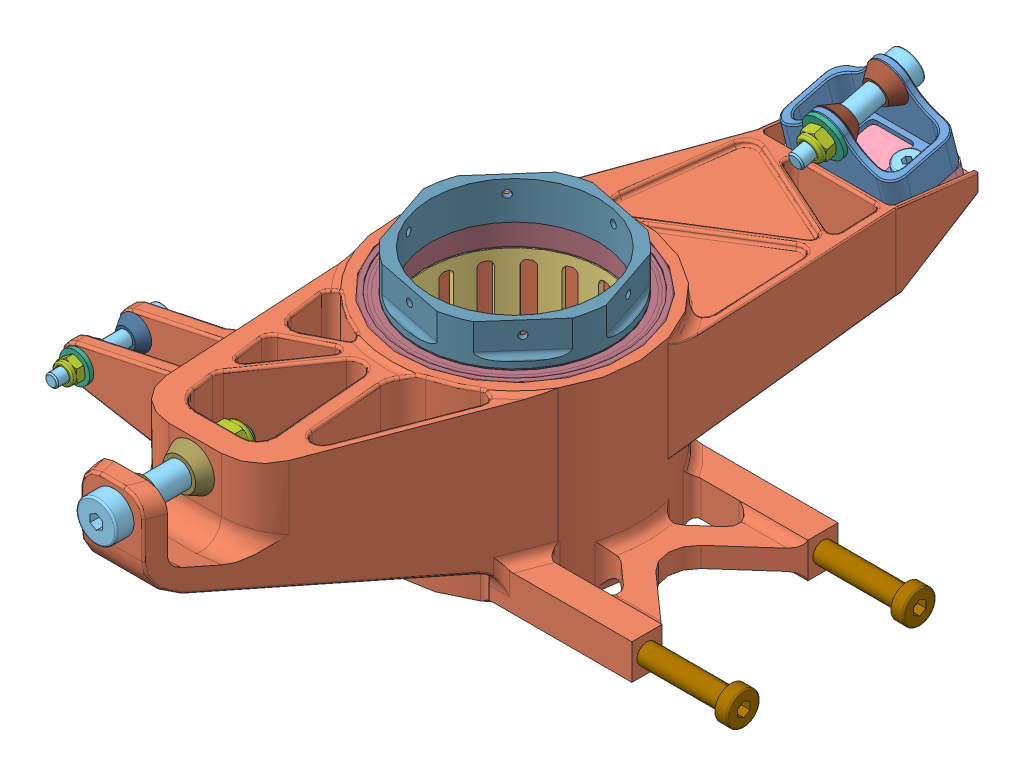
SolidWorks assembly LustroPUTM-S-SF-WT-Upright-Assembly, configuration Domyślna. Lengths in mm.
Overall size (218.59 95.83 300.66).
30 component instances, 14 part files, 0 mates.
Components (placement in the parent):
- LustroPUTM-S-SF-WT-U-Clevis_Upper-1: LustroPUTM-S-SF-WT-U-Clevis_Upper [Domyślna] at (-185.991 125.9219 -157.0973) x (-1 0 0) z (0 0.241922 -0.970296) size (48 28 28)
- LustroPUTM-S-SF-WT-Upright_new-1: LustroPUTM-S-SF-WT-Upright_new [Domyślna] at (-200.991 98.9781 -15.9367) x (-1 0 0) z (0 1 0) size (178.6 286.5 74.07)
- LustroPUTM-S-SF-WT-U-RearDistanceRing-1: LustroPUTM-S-SF-WT-U-RearDistanceRing [Domyślna] at (-200.991 95.4781 -15.9367) x (0.988942 0 -0.148304) z (0.148304 0 0.988942) size (74 53 74)
- LustroPUTM-S-SF-WT-U-Shim-1: LustroPUTM-S-SF-WT-U-Shim [5 mm] at (-185.991 122.535 -143.5132) x (1 0 0) z (0 0.970296 0.241922) size (48 35 5)
- LustroPUTM-FT-ELESA_ISO7379-1: LustroPUTM-FT-ELESA_ISO7379 [8-M6-30] at (-185.991 146.6584 -157.5955) x (0 0.241922 -0.970296) z (0.965514 0.252619 0.062985) size (46.5 13 13)
- LustroPUTM-FT-FABORY_ISO7089-1: LustroPUTM-FT-FABORY_ISO7089 [M8 [38093.080.001]] at (-185.991 138.1669 -123.5381) x (0.998204 0.058133 0.014494) z (0 -0.241922 0.970296) size (16 16 1.6)
- LustroPUTM-FT-FABORY_DIN985-1: LustroPUTM-FT-FABORY_DIN985 [M6 [12348.060.001]] at (-185.991 138.1669 -123.5381) x (-0.958831 -0.275543 -0.0687) z (0 0.241922 -0.970296) size (11.9 10.35 6.18)
- LustroPUTM-FT-ELESA_ISO7379-2: LustroPUTM-FT-ELESA_ISO7379 [6-M5-12] at (-200.991 128.8419 -141.9407) x (0 0.970296 0.241922) z (0.631634 -0.187554 0.752238) size (24.5 10 10)
- LustroPUTM-FT-ELESA_ISO7379-3: LustroPUTM-FT-ELESA_ISO7379 [6-M5-12] at (-170.991 128.8419 -141.9407) x (0 0.970296 0.241922) z (-0.531908 -0.20486 0.821648) size (24.5 10 10)
- LustroPUTM-FT-FABORY_DIN985-2: LustroPUTM-FT-FABORY_DIN985 [M5 [12348.050.001]] at (-200.991 113.8888 -145.6689) x (0.916575 -0.096735 0.387984) z (0 0.970296 0.241922) size (9.51 8.27 5.13)
- LustroPUTM-FT-FABORY_DIN985-3: LustroPUTM-FT-FABORY_DIN985 [M5 [12348.050.001]] at (-170.991 113.8888 -145.6689) x (0.876116 0.116631 -0.46778) z (0 0.970296 0.241922) size (9.51 8.27 5.13)
- LustroPUTM-FT-ELESA_ISO7379-4: LustroPUTM-FT-ELESA_ISO7379 [10-M8-40] at (-215.991 120.4781 135.5633) x (0 0 1) z (-0.99999 -0.004422 0) size (60 16 16)
- LustroPUTM-FT-FABORY_ISO7089-2: LustroPUTM-FT-FABORY_ISO7089 [M8 [38093.080.001]] at (-215.991 120.4781 87.5633) x (0.992083 0.125585 0) z (0 0 1) size (16 16 1.6)
- LustroPUTM-FT-FABORY_DIN985-4: LustroPUTM-FT-FABORY_DIN985 [M8 [12348.080.001]] at (-215.991 120.4781 85.9633) size (15.49 13.47 8.24)
- LustroPUTM-FT-ELESA_ISO7379-5: LustroPUTM-FT-ELESA_ISO7379 [6-M5-30] at (-284.991 108.9781 40.5633) x (0 0 -1) z (-0.999708 0.024164 0) size (44 10 10)
- LustroPUTM-FT-FABORY_ISO7089-3: LustroPUTM-FT-FABORY_ISO7089 [M6 [38093.060.001]] at (-284.991 108.9781 75.1633) size (12 12 1.6)
- LustroPUTM-FT-FABORY_DIN985-5: LustroPUTM-FT-FABORY_DIN985 [M5 [12348.050.001]] at (-284.991 108.9781 75.1633) x (-0.913064 0.407815 0) z (0 0 -1) size (9.51 8.27 5.13)
- LustroWasher-5mm-1: LustroWasher-5mm [Domyślna] at (-200.991 113.8888 -145.6689) x (1 0 0) z (0 -0.241922 0.970296) size (10 1 10)
- LustroWasher-5mm-2: LustroWasher-5mm [Domyślna] at (-170.991 114.8591 -145.427) x (1 0 0) z (0 0.241922 -0.970296) size (10 1 10)
- LustroPUTM-FT-FABORY_DIN7984-1: LustroPUTM-FT-FABORY_DIN7984 [M8x60 [07090.080.060]] at (-74.891 68.2281 -50.9367) x (1 0 0) z (0 0.999978 0.006558) size (65 13 13)
- LustroPUTM-FT-FABORY_DIN7984-2: LustroPUTM-FT-FABORY_DIN7984 [M8x60 [07090.080.060]] at (-74.891 68.2281 19.0633) x (1 0 0) z (0 0.999978 0.006558) size (65 13 13)
- LustroPUTM-S-Grzybek_6mm-1: LustroPUTM-S-Grzybek_6mm [Domyślna] at (-284.991 108.9781 51.0633) x (1 0 0) z (0 -1 0) size (13 4 13)
- LustroPUTM-S-Grzybek_6mm-2: LustroPUTM-S-Grzybek_6mm [Domyślna] at (-284.991 108.9781 68.0633) x (-0.923728 -0.383049 0) z (0.383049 -0.923728 0) size (13 4 13)
- LustroPUTM-S-Grzybek_8mm-1: LustroPUTM-S-Grzybek_8mm [Domyślna] at (-185.991 139.2798 -128.0015) x (0.855967 0.501672 0.125081) z (-0.51703 0.830541 0.207077) size (16 5 16)
- LustroPUTM-S-Grzybek_8mm-2: LustroPUTM-S-Grzybek_8mm [Domyślna] at (-185.991 144.602 -149.348) x (-0.345694 0.910474 0.227007) z (0.938347 0.335426 0.083631) size (16 5 16)
- LustroPUTM-S-Grzybek_10mm-1: LustroPUTM-S-Grzybek_10mm [Domyślna] at (-215.991 120.4781 121.5633) x (0.984486 0.175462 0) z (-0.175462 0.984486 0) size (18 5 18)
- LustroPUTM-S-Grzybek_10mm-2: LustroPUTM-S-Grzybek_10mm [Domyślna] at (-215.991 120.4781 97.5633) x (0.680718 -0.732546 0) z (-0.732546 -0.680718 0) size (18 5 18)
- LustroPUTM-S-SF-WT-Bearing-1: LustroPUTM-S-SF-WT-Bearing [Domyślna] at (-200.991 68.9781 -15.9367) x (0 -1 0) z (0 0 1) size (10 90 90)
- LustroPUTM-S-SF-WT-Bearing-2: LustroPUTM-S-SF-WT-Bearing [Domyślna] at (-200.991 131.9781 -15.9367) x (0 -1 0) z (0 0 1) size (10 90 90)
- LustroPUTM-S-SF-WT-Hubnut-1: LustroPUTM-S-SF-WT-Hubnut [Domyślna] at (-200.991 131.9781 -15.9367) x (-0.980593 0 -0.196056) z (0 -1 0) size (76.5 76.5 15)
